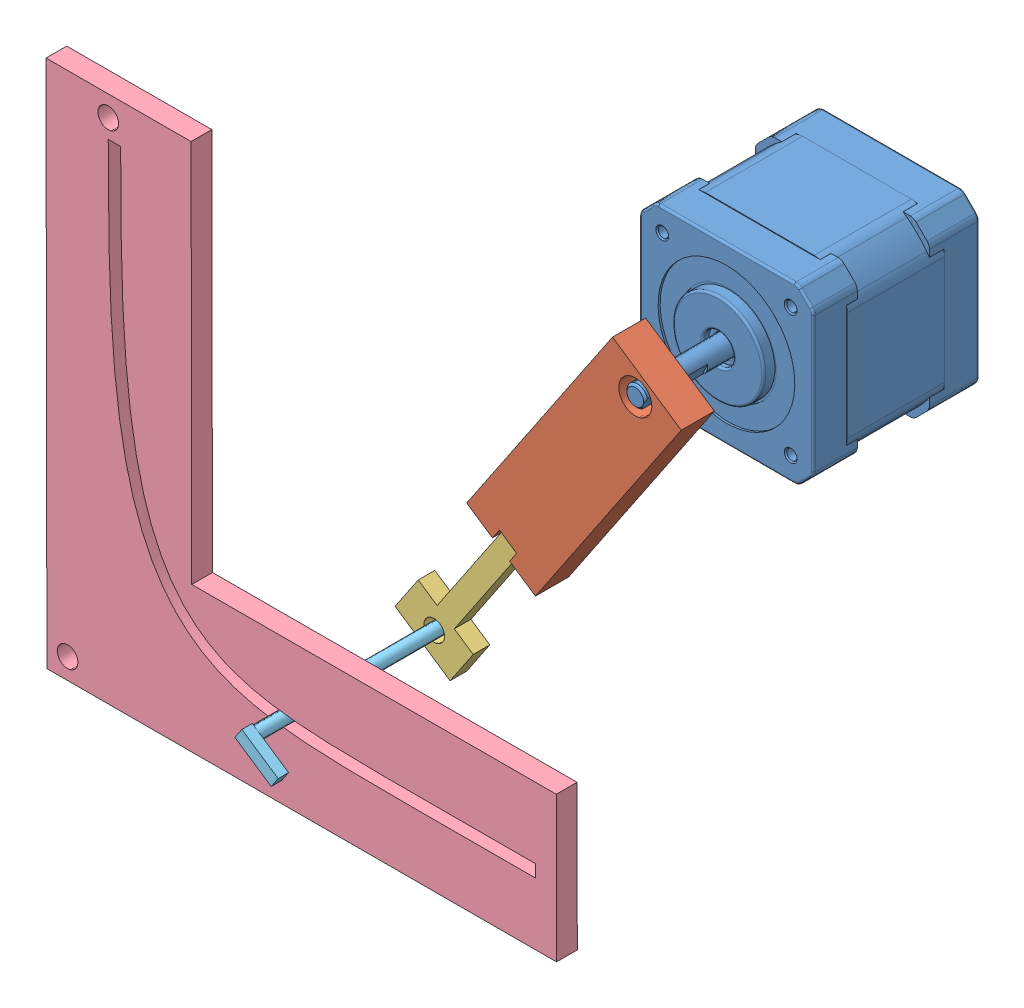
SolidWorks assembly gripper_motion_assembly, configuration Default. Lengths in mm.
Overall size (128.42 127.72 106).
6 component instances, 5 part files, 6 mates.
Components (placement in the parent):
- nema  17-1: nema  17 [По умолчанию] at (125.4134 110.615 -13.7512) x (1 0 0) z (0 -1 0) size (42.3 62 51.35)
- extension_rods-2: extension_rods [Default] at (55.775 66.9667 -7.5797) x (0.829539 -0.558449 0) z (0 0 1) size (20 108.04 8) (flexible)
  - female_extension-1: female_extension [Default] at (33.3924 20.0974 51.8285) size (20 63 8)
  - male_extension-1: male_extension [Default] at (33.3924 -10.4035 49.8285) x (1 0 0) z (0 -1 0) size (16 4 55)
- travel_path3-2: travel_path3 [Default] at (36.3283 35.7824 78.1918) x (0.999999 0.0017 0) z (0 0 1) size (123 127.51 5)
- slider_crank2-1: slider_crank2 [Default] at (74.8732 35.541 42.2488) x (0.829539 -0.558449 0) z (-0.558449 -0.829539 0) size (10.55 50 3)
Mates (geometry in assembly coordinates):
- Concentric4: concentric aligned: cylinder of nema  17-1 through (125.4134 110.615 48.2488) axis (0 0 -1) radius 2.5; cylinder of extension_rods-2/female_extension-1 through (125.4134 110.615 48.2488) axis (0 0 -1) radius 4
- Coincident11: coincident aligned: plane of nema  17-1 through (125.4134 110.615 48.2488) normal (0 0 1); plane of extension_rods-2/female_extension-1 through (115.1864 106.0974 48.2488) normal (0 0 1)
- Concentric5: concentric anti-aligned: cylinder of extension_rods-2/male_extension-1 through (121.7772 34.4278 36.2488) axis (0 0 1) radius 2.5; cylinder of slider_crank2-1 through (121.7772 34.4278 92.2488) axis (0 0 -1) radius 1.5
- Coincident13: coincident aligned: plane of extension_rods-2/male_extension-1 through (122.0156 39.4221 42.2488) normal (0 0 -1); plane of slider_crank2-1 through (121.7772 34.4278 42.2488) normal (0 0 -1)
- Tangent10: tangent: face of travel_path3-2; cylinder of ? through (121.7772 34.4278 92.2488) axis (0 0 -1) radius 1.5
- Parallel11: parallel aligned: plane of extension_rods-2/male_extension-1 through (122.0156 39.4221 42.2488) normal (0.047672 0.998863 0); plane of slider_crank2-1 through (121.8487 35.9261 42.2488) normal (0.047672 0.998863 0)
